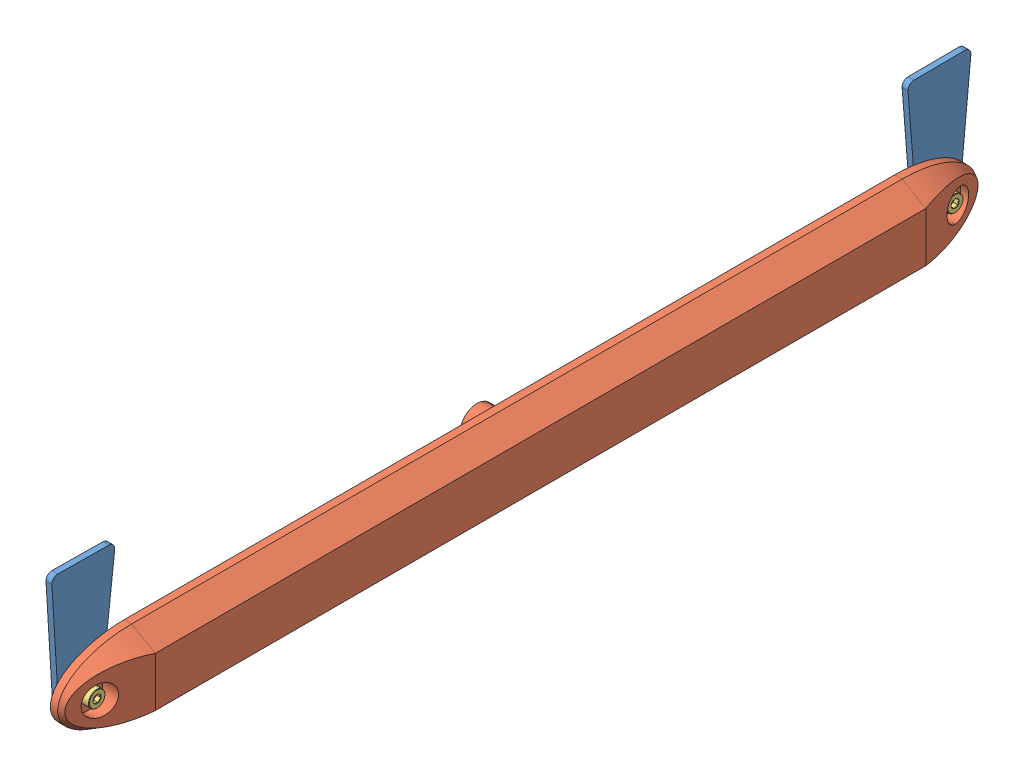
SolidWorks assembly EL-A0106-AA-Brake Light Assembly, configuration Default. Lengths in mm.
Overall size (29.39 75.53 438.47).
8 component instances, 5 part files, 15 mates.
Components (placement in the parent):
- Part3^EL-A0106-AA-Brake Light Assembly-1: Part3^EL-A0106-AA-Brake Light Assembly [Default] at origin (virtual)
- EL-30080-AA-Brake Light Tabs-3: EL-30080-AA-Brake Light Tabs [Default] at (-2.54 45.9963 210.4863) x (0 -0.821175 -0.570677) z (1 0 0) size (54.73 47.73 2.54)
- EL-00081-AA-Brake light-3: EL-00081-AA-Brake light [Default] at (0 0 27.431) x (1 0 0) z (0 -1 0) size (29.39 396.07 33.03)
- EL-30080-AA-Brake Light Tabs-4: EL-30080-AA-Brake Light Tabs [Default] at (-2.54 46.0085 -156.9817) x (0 -0.810721 -0.585433) z (1 0 0) size (54.73 47.73 2.54)
- BR-Black Oxide C12.9 SHCS, M4x0.7-12 (91290A148)-1: BR-Black Oxide C12.9 SHCS, M4x0.7-12 (91290A148) [91290A148] at (-0.825 0 211.581) x (0 -0.971346 0.237672) z (1 0 0) size (7 7 16.17)
- BR-Black Oxide C12.9 SHCS, M4x0.7-12 (91290A148)-2: BR-Black Oxide C12.9 SHCS, M4x0.7-12 (91290A148) [91290A148] at (-0.825 0 -156.719) x (0 -0.217734 -0.976008) z (1 0 0) size (7 7 16.17)
- FS-NYLOC C8 HX, M4x0.7-5 (90576A103)-2: FS-NYLOC C8 HX, M4x0.7-5 (90576A103) [90576A103] at (-5.04 0 -156.719) x (0 1 0.000143) z (-1 0 0) size (7 8.08 5)
- FS-NYLOC C8 HX, M4x0.7-5 (90576A103)-3: FS-NYLOC C8 HX, M4x0.7-5 (90576A103) [90576A103] at (-5.04 0 211.581) x (0 -0.000143 1) z (-1 0 0) size (7 8.08 5)
Mates (geometry in assembly coordinates):
- Concentric3: concentric anti-aligned: circle of brake light tabs-3; circle of EL-000XX-AA-Brake Light, 15in-3
- Concentric4: concentric anti-aligned: circle of EL-000XX-AA-Brake Light, 15in-3; circle of brake light tabs-4
- Coincident1: coincident aligned: cylinder of EL-30080-AA-Brake Light Tabs-4 through (0 0 -156.719) axis (-1 0 0) radius 3.3; circle of BR-Black Oxide C12.9 SHCS, M4x0.7-12 (91290A148)-2
- Concentric9: concentric aligned: cylinder of EL-30080-AA-Brake Light Tabs-3 through (0 0 211.581) axis (-1 0 0) radius 3.3; cylinder of BR-Black Oxide C12.9 SHCS, M4x0.7-12 (91290A148)-1 through (-8.825 0 211.581) axis (-1 0 0) radius 2
- Coincident2: coincident anti-aligned: plane of EL-00081-AA-Brake light-3 through (0 0 -137.9357) normal (-1 0 0); plane of EL-30080-AA-Brake Light Tabs-4 through (0 0 -156.719) normal (1 0 0)
- Coincident3: coincident anti-aligned: plane of EL-30080-AA-Brake Light Tabs-3 through (0 0 211.581) normal (1 0 0); plane of EL-00081-AA-Brake light-3 through (0 0 -137.9357) normal (-1 0 0)
- Coincident4: coincident anti-aligned: plane of EL-00081-AA-Brake light-3 through (3.175 0 211.581) normal (1 0 0); plane of BR-Black Oxide C12.9 SHCS, M4x0.7-12 (91290A148)-1 through (3.175 -0.7843 208.3755) normal (-1 0 0)
- Coincident5: coincident anti-aligned: plane of EL-00081-AA-Brake light-3 through (3.175 0 -156.719) normal (1 0 0); plane of BR-Black Oxide C12.9 SHCS, M4x0.7-12 (91290A148)-2 through (3.175 3.2208 -157.4376) normal (-1 0 0)
- Concentric10: concentric anti-aligned: cylinder of BR-Black Oxide C12.9 SHCS, M4x0.7-12 (91290A148)-2 through (-8.825 0 -156.719) axis (-1 0 0) radius 2; cylinder of FS-NYLOC C8 HX, M4x0.7-5 (90576A103)-2 through (-7.54 0 -156.719) axis (1 0 0) radius 2
- Coincident7: coincident anti-aligned: plane of EL-30080-AA-Brake Light Tabs-4 through (-2.54 0 -156.719) normal (-1 0 0); plane of FS-NYLOC C8 HX, M4x0.7-5 (90576A103)-2 through (-2.54 0 -156.719) normal (1 0 0)
- Concentric11: concentric anti-aligned: cylinder of BR-Black Oxide C12.9 SHCS, M4x0.7-12 (91290A148)-1 through (-8.825 0 211.581) axis (-1 0 0) radius 2; cylinder of FS-NYLOC C8 HX, M4x0.7-5 (90576A103)-3 through (-7.54 0 211.581) axis (1 0 0) radius 2
- Coincident8: coincident anti-aligned: plane of EL-30080-AA-Brake Light Tabs-3 through (-2.54 0 211.581) normal (-1 0 0); plane of FS-NYLOC C8 HX, M4x0.7-5 (90576A103)-3 through (-2.54 0 211.581) normal (1 0 0)
- Coincident9: coincident anti-aligned: plane of EL-00081-AA-Brake light-3 through (0 0 27.431) normal (0 -1 0)
- Coincident10: coincident aligned: plane of EL-00081-AA-Brake light-3 through (0 0 27.431) normal (1 0 0)
- Coincident11: coincident anti-aligned: plane of EL-00081-AA-Brake light-3 through (0 0 27.431) normal (0 -1 0)
